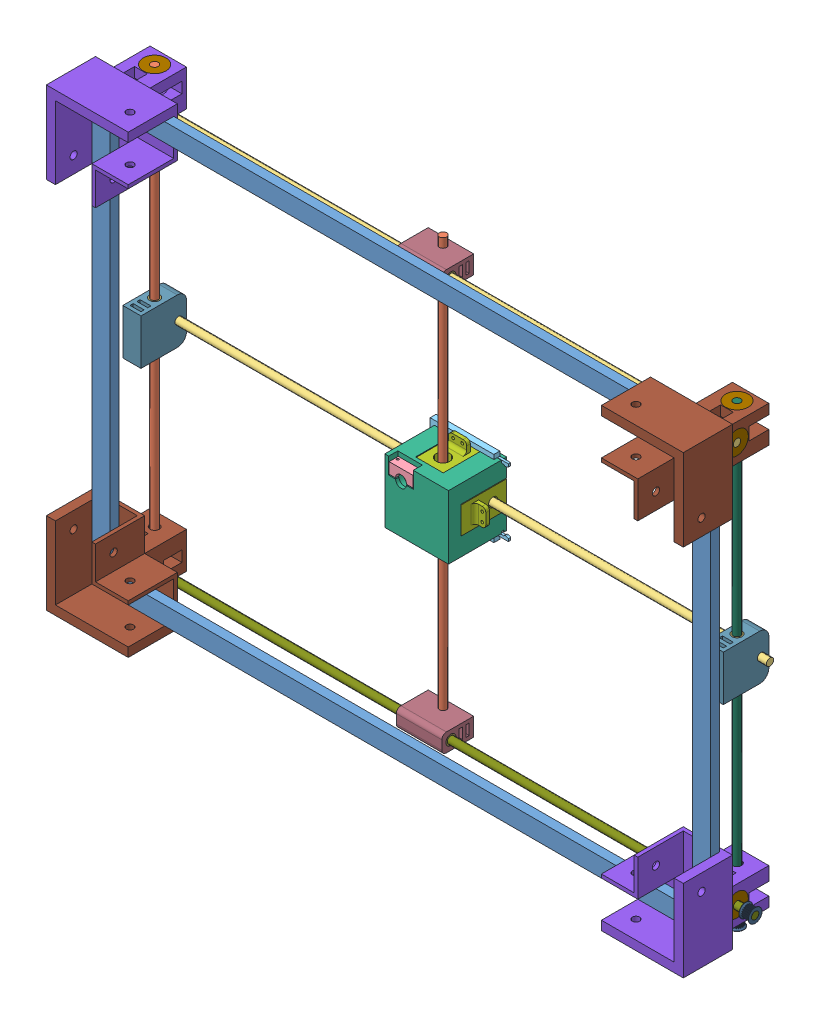
SolidWorks assembly Assemblage_XY, configuration Défaut. Lengths in mm.
Overall size (710 510 120.3).
50 component instances, 16 part files, 70 mates.
Components (placement in the parent):
- Cadre_XY-1: Cadre_XY [Défaut] at (379.0068 -247.2078 675) size (680 480 10)
- AXE_8X480-2: AXE_8X480 [Défaut] at (-280.9932 -247.2078 636) x (0.987721 0 0.156231) z (0 1 0) size (8 8 480)
- AXE_8X680-1: AXE_8X680 [Défaut] at (379.0068 212.7922 656) x (0 0.013067 0.999915) z (-1 0 0) size (8 8 680)
- AXE_8X480-3: AXE_8X480 [Défaut] at (39.6568 232.7922 639.7) x (0.999527 0 0.030742) z (0 -1 0) size (8 8 480)
- AXE_8X680-3: AXE_8X680 [Défaut] at (-300.9932 -14.107 619.7) x (0 -0.696158 -0.717888) z (1 0 0) size (8 8 680)
- P3DMIPC-Tête_complete-1: P3DMIPC-Tête_complete [Défaut] at (-4.5359 -0.7369 635.2981) x (0 1 0) z (1 0 0) size (94 64.01 96.63)
  - P3DMIPC-Clip_Buse_E3D-1: P3DMIPC-Clip_Buse_E3D [Défaut] at (17.0518 23.4109 40.0035) x (1 0 0) z (0 1 0) size (12 26 10)
  - P3DMIPC-Clip_tête-1: P3DMIPC-Clip_tête [Défaut] at (26.9018 -25.0891 4.5597) x (1 0 0) z (0 -1 0) size (84 92 6.55)
  - P3DMIPC-Porte_Buse_E3DX1-1: P3DMIPC-Porte_Buse_E3DX1 [Défaut] at (22.03 33.4019 79.1927) x (0 0 1) z (0 -1 0) size (70 70 64)
  - P3DMIPC-Chariot-1: P3DMIPC-Chariot [Défaut] at (-48.37 -30.5981 79.1927) size (94 50 94)
- Angle_magique_G-1: Angle_magique_G [Défaut] at (379.0068 -247.2078 675) x (-1 0 0) z (0 0 -1) size (90 90 104)
- F608ZZ-1: F608ZZ [Défaut] at (372.0068 -227.2078 656) x (0 -0.924225 -0.381849) z (1 0 0) size (25 25 7)
- Angle_magique_G-4: Angle_magique_G [Défaut] at (-300.9932 232.7922 675) x (1 0 0) z (0 0 -1) size (90 90 104)
- pulley_gt2_3mm_20t-10: pulley_gt2_3mm_20t [Défaut] at (-280.9932 209.5422 636) x (0.106795 0 0.994281) z (0 1 0) size (15 15 10.5)
- pulley_gt2_3mm_20t-11: pulley_gt2_3mm_20t [Défaut] at (-277.7432 212.7922 656) x (0 0.106795 0.994281) z (-1 0 0) size (15 15 10.5)
- pulley_gt2_3mm_20t-12: pulley_gt2_3mm_20t [Défaut] at (-280.9932 -236.4578 636) x (-0.771074 0 0.636745) z (0 1 0) size (15 15 10.5)
- pulley_gt2_3mm_20t-13: pulley_gt2_3mm_20t [Défaut] at (-277.7432 -227.2078 656) x (0 0.106795 0.994281) z (-1 0 0) size (15 15 10.5)
- pulley_gt2_3mm_20t-15: pulley_gt2_3mm_20t [Défaut] at (359.0068 222.0422 636) x (-0.106795 0 0.994281) z (0 -1 0) size (15 15 10.5)
- pulley_gt2_3mm_20t-16: pulley_gt2_3mm_20t [Défaut] at (368.2568 212.7922 656) x (0 0.106795 0.994281) z (-1 0 0) size (15 15 10.5)
- F608ZZ-2: F608ZZ [Défaut] at (-280.9932 225.7922 636) x (-0.546944 0 0.837169) z (0 1 0) size (25 25 7)
- F608ZZ-3: F608ZZ [Défaut] at (-293.9932 212.7922 656) x (0 0 1) z (-1 0 0) size (25 25 7)
- F608ZZ-4: F608ZZ [Défaut] at (-293.9932 -227.2078 656) x (0 0 1) z (-1 0 0) size (25 25 7)
- F608ZZ-5: F608ZZ [Défaut] at (-280.9932 -240.2078 636) x (-0.924225 0 -0.381849) z (0 -1 0) size (25 25 7)
- F608ZZ-6: F608ZZ [Défaut] at (359.0068 -240.2078 636) x (-0.546944 0 0.837169) z (0 -1 0) size (25 25 7)
- F608ZZ-7: F608ZZ [Défaut] at (372.0068 212.7922 656) x (0 0 1) z (1 0 0) size (25 25 7)
- F608ZZ-8: F608ZZ [Défaut] at (359.0068 225.7922 636) x (0 0 1) z (0 1 0) size (25 25 7)
- Angle_magique_D-1: Angle_magique_D [Défaut] at (-300.9932 -247.2078 675) x (0 1 0) z (0 0 -1) size (90 90 104)
- Angle_magique_D-2: Angle_magique_D [Défaut] at (379.0068 232.7922 675) x (0 -1 0) z (0 0 -1) size (90 90 104)
- Assemblage_glissière_block_belt_palier_AR-1: Assemblage_glissière_block_belt_palier_AR [Défaut] at (160.1817 -186.4667 609.4689) x (0 -1 0) z (-1 0 0) size (20 35 50)
  - ultimaker_cuivre_fritté_douille_8mmx11mmx22 mm-1: ultimaker_cuivre_fritté_douille_8mmx11mmx22 mm [Défaut] at (40.7411 46.5311 95.5249) size (11 11 22)
  - ultimaker_cuivre_fritté_douille_8mmx11mmx22 mm-2: ultimaker_cuivre_fritté_douille_8mmx11mmx22 mm [Défaut] at (40.7411 46.5311 123.5249) size (11 11 22)
  - Glisière_block_belt_AR-2: Glisière_block_belt_AR [Défaut] at (50.7411 14.5311 95.5249) size (20 35 50)
- Assemblage_glissière_block_belt_palier_AR-2: Assemblage_glissière_block_belt_palier_AR [Défaut] at (-80.8682 172.0511 609.4689) x (0 1 0) z (1 0 0) size (20 35 50)
  - ultimaker_cuivre_fritté_douille_8mmx11mmx22 mm-1: ultimaker_cuivre_fritté_douille_8mmx11mmx22 mm [Défaut] at (40.7411 46.5311 95.5249) size (11 11 22)
  - ultimaker_cuivre_fritté_douille_8mmx11mmx22 mm-2: ultimaker_cuivre_fritté_douille_8mmx11mmx22 mm [Défaut] at (40.7411 46.5311 123.5249) size (11 11 22)
  - Glisière_block_belt_AR-2: Glisière_block_belt_AR [Défaut] at (50.7411 14.5311 95.5249) size (20 35 50)
- pulley_gt2_3mm_20t-17: pulley_gt2_3mm_20t [Défaut] at (368.2568 -227.2078 656) x (0 0.106795 0.994281) z (-1 0 0) size (15 15 10.5)
- pulley_gt2_3mm_20t-18: pulley_gt2_3mm_20t [Défaut] at (359.0068 -223.9578 636) x (0.203502 0 0.979074) z (0 -1 0) size (15 15 10.5)
- Assemblage_glissière_block_belt_palier_GD-1: Assemblage_glissière_block_belt_palier_GD [Défaut] at (364.4936 -89.107 631.6132) x (-1 0 0) z (0 1 0) size (20 50 50)
  - Glisière_block_belt_GD-1: Glisière_block_belt_GD [Défaut] at (15.4869 -20.6132 50) size (20 50 50)
  - ultimaker_cuivre_fritté_douille_8mmx11mmx22 mm-1: ultimaker_cuivre_fritté_douille_8mmx11mmx22 mm [Défaut] at (5.4869 4.3868 50) size (11 11 22)
  - ultimaker_cuivre_fritté_douille_8mmx11mmx22 mm-2: ultimaker_cuivre_fritté_douille_8mmx11mmx22 mm [Défaut] at (5.4869 4.3868 78) size (11 11 22)
- Assemblage_glissière_block_belt_palier_GD-2: Assemblage_glissière_block_belt_palier_GD [Défaut] at (-286.4801 60.893 631.6132) x (1 0 0) z (0 -1 0) size (20 50 50)
  - Glisière_block_belt_GD-1: Glisière_block_belt_GD [Défaut] at (15.4869 -20.6132 50) size (20 50 50)
  - ultimaker_cuivre_fritté_douille_8mmx11mmx22 mm-1: ultimaker_cuivre_fritté_douille_8mmx11mmx22 mm [Défaut] at (5.4869 4.3868 50) size (11 11 22)
  - ultimaker_cuivre_fritté_douille_8mmx11mmx22 mm-2: ultimaker_cuivre_fritté_douille_8mmx11mmx22 mm [Défaut] at (5.4869 4.3868 78) size (11 11 22)
- AXE_8X500_Moteur-1: AXE_8X500_Moteur [Défaut] at (359.0068 -267.2078 636) x (0.283264 0 -0.959042) z (0 1 0) size (8 8 500)
- AXE_8X700_Moteur-1: AXE_8X700_Moteur [Défaut] at (399.0068 -227.2078 656) x (0 0 1) z (-1 0 0) size (8 8 700)
- pulley_gt2_3mm_20t-19: pulley_gt2_3mm_20t [Défaut] at (359.0068 -255.7078 636) x (0.203502 0 0.979074) z (0 -1 0) size (15 15 10.5)
- pulley_gt2_3mm_20t-20: pulley_gt2_3mm_20t [Défaut] at (387.5068 -227.2078 656) x (0 0.203502 0.979074) z (1 0 0) size (15 15 10.5)
Mates (geometry in assembly coordinates):
- Coaxiale1: concentric anti-aligned: cylinder of AXE_8X680-3 through (379.0068 -14.107 619.7) axis (-1 0 0) radius 4; cylinder of P3DMIPC-Tête_complete-1/P3DMIPC-Chariot-1 through (70.6568 -14.107 619.7) axis (1 0 0) radius 5
- Coaxiale2: concentric anti-aligned: cylinder of AXE_8X480-3 through (39.6568 -247.2078 639.7) axis (0 1 0) radius 4; cylinder of P3DMIPC-Tête_complete-1/P3DMIPC-Chariot-1 through (39.6568 -45.107 639.7) axis (0 -1 0) radius 5
- Coïncidente14: coincident anti-aligned: plane of Cadre_XY-1 through (379.0068 -247.2078 675) normal (0 0 -1); plane of Angle_magique_G-1 through (379.0068 -247.2078 675) normal (0 0 1)
- Coïncidente15: coincident anti-aligned: plane of Cadre_XY-1 through (379.0068 -247.2078 685) normal (1 0 0); plane of Angle_magique_G-1 through (379.0068 -247.2078 725) normal (-1 0 0)
- Coïncidente16: coincident anti-aligned: plane of Cadre_XY-1 through (379.0068 -247.2078 685) normal (0 -1 0); plane of Angle_magique_G-1 through (299.0068 -247.2078 725) normal (0 1 0)
- Coïncidente27: coincident anti-aligned: plane of Cadre_XY-1 through (379.0068 -247.2078 675) normal (0 0 -1); plane of Angle_magique_G-4 through (-300.9932 232.7922 675) normal (0 0 1)
- Coïncidente28: coincident anti-aligned: plane of Cadre_XY-1 through (379.0068 232.7922 685) normal (0 1 0); plane of Angle_magique_G-4 through (-220.9932 232.7922 725) normal (0 -1 0)
- Coïncidente29: coincident anti-aligned: plane of Cadre_XY-1 through (-300.9932 -247.2078 685) normal (-1 0 0); plane of Angle_magique_G-4 through (-300.9932 232.7922 725) normal (1 0 0)
- Coaxiale17: concentric anti-aligned: cylinder of AXE_8X680-1 through (-300.9932 212.7922 656) axis (1 0 0) radius 4; cylinder of pulley_gt2_3mm_20t-11 through (-277.7432 212.7922 656) axis (-1 0 0) radius 4
- Coaxiale18: concentric aligned: cylinder of AXE_8X680-1 through (-300.9932 212.7922 656) axis (1 0 0) radius 4; cylinder of Angle_magique_G-4 through (-310.9932 212.7922 656) axis (1 0 0) radius 5
- Coïncidente30: coincident aligned: plane of Cadre_XY-1 through (-300.9932 -247.2078 685) normal (-1 0 0); plane of AXE_8X680-1 through (-300.9932 212.7922 656) normal (-1 0 0)
- Distance2: distance = 2.75 mm anti-aligned: plane of pulley_gt2_3mm_20t-11 through (-278.7432 212.7922 656) normal (1 0 0); plane of Angle_magique_G-4 through (-275.9932 192.7922 621) normal (-1 0 0)
- Coaxiale19: concentric anti-aligned: cylinder of AXE_8X680-1 through (-300.9932 212.7922 656) axis (1 0 0) radius 4; cylinder of pulley_gt2_3mm_20t-16 through (368.2568 212.7922 656) axis (-1 0 0) radius 4
- Coaxiale24: concentric aligned: cylinder of AXE_8X480-2 through (-280.9932 232.7922 636) axis (0 -1 0) radius 4; cylinder of Angle_magique_G-4 through (-280.9932 232.7923 636) axis (0 -1 0) radius 5
- Coaxiale25: concentric anti-aligned: cylinder of AXE_8X480-2 through (-280.9932 232.7922 636) axis (0 -1 0) radius 4; cylinder of pulley_gt2_3mm_20t-10 through (-280.9932 209.5422 636) axis (0 1 0) radius 4
- Coïncidente34: coincident aligned: plane of Cadre_XY-1 through (379.0068 232.7922 685) normal (0 1 0); plane of AXE_8X480-2 through (-280.9932 232.7922 636) normal (0 1 0)
- Distance4: distance = 2.75 mm anti-aligned: plane of pulley_gt2_3mm_20t-10 through (-280.9932 210.5422 636) normal (0 -1 0); plane of Angle_magique_G-4 through (-275.9932 207.7922 621) normal (0 1 0)
- Coaxiale26: concentric anti-aligned: cylinder of AXE_8X480-2 through (-280.9932 232.7922 636) axis (0 -1 0) radius 4; cylinder of pulley_gt2_3mm_20t-12 through (-280.9932 -236.4578 636) axis (0 1 0) radius 4
- Coïncidente44: coincident anti-aligned: plane of Cadre_XY-1 through (379.0068 -247.2078 675) normal (0 0 -1); plane of Angle_magique_D-1 through (-300.9932 -247.2078 675) normal (0 0 1)
- Coïncidente45: coincident anti-aligned: plane of Cadre_XY-1 through (379.0068 -247.2078 685) normal (0 -1 0); plane of Angle_magique_D-1 through (-300.9932 -247.2078 725) normal (0 1 0)
- Coïncidente46: coincident anti-aligned: plane of Cadre_XY-1 through (-300.9932 -247.2078 685) normal (-1 0 0); plane of Angle_magique_D-1 through (-300.9932 -167.2078 725) normal (1 0 0)
- Distance10: distance = 2.75 mm anti-aligned: plane of Angle_magique_D-1 through (-260.9932 -222.2078 621) normal (0 -1 0); plane of pulley_gt2_3mm_20t-12 through (-280.9932 -224.9578 636) normal (0 1 0)
- Coïncidente51: coincident anti-aligned: plane of Cadre_XY-1 through (379.0068 -247.2078 675) normal (0 0 -1); plane of Angle_magique_D-2 through (379.0068 232.7922 675) normal (0 0 1)
- Coïncidente52: coincident anti-aligned: plane of Cadre_XY-1 through (379.0068 232.7922 685) normal (0 1 0); plane of Angle_magique_D-2 through (379.0068 232.7922 725) normal (0 -1 0)
- Coïncidente53: coincident anti-aligned: plane of Cadre_XY-1 through (379.0068 -247.2078 685) normal (1 0 0); plane of Angle_magique_D-2 through (379.0068 152.7922 725) normal (-1 0 0)
- Distance11: distance = 2.75 mm anti-aligned: plane of pulley_gt2_3mm_20t-15 through (359.0068 210.5422 636) normal (0 -1 0); plane of Angle_magique_D-2 through (339.0068 207.7922 621) normal (0 1 0)
- Distance12: distance = 2.75 mm anti-aligned: plane of Angle_magique_D-2 through (354.0068 207.7922 621) normal (1 0 0); plane of pulley_gt2_3mm_20t-16 through (356.7568 212.7922 656) normal (-1 0 0)
- Coaxiale39: concentric anti-aligned: cylinder of AXE_8X680-1 through (-300.9932 212.7922 656) axis (1 0 0) radius 4; cylinder of Assemblage_glissière_block_belt_palier_AR-2/ultimaker_cuivre_fritté_douille_8mmx11mmx22 mm-1 through (36.6568 212.7922 656) axis (-1 0 0) radius 4
- Coaxiale42: concentric anti-aligned: cylinder of AXE_8X480-3 through (39.6568 -247.2078 639.7) axis (0 1 0) radius 4; cylinder of Assemblage_glissière_block_belt_palier_AR-2/Glisière_block_belt_AR-2 through (39.6568 222.7922 639.7) axis (0 -1 0) radius 4
- Coaxiale43: concentric aligned: cylinder of AXE_8X480-3 through (39.6568 -247.2078 639.7) axis (0 1 0) radius 4; cylinder of Assemblage_glissière_block_belt_palier_AR-1/Glisière_block_belt_AR-2 through (39.6568 -237.2078 639.7) axis (0 1 0) radius 4
- Coaxiale50: concentric anti-aligned: cylinder of F608ZZ-7 through (377.5068 212.7922 656) axis (-1 0 0) radius 11; cylinder of Angle_magique_D-2 through (372.0068 212.7922 656) axis (1 0 0) radius 11
- Coïncidente63: coincident anti-aligned: plane of F608ZZ-7 through (372.0068 212.7922 656) normal (-1 0 0); plane of Angle_magique_D-2 through (372.0068 212.7922 656) normal (1 0 0)
- Coaxiale51: concentric anti-aligned: cylinder of F608ZZ-8 through (359.0068 231.2922 636) axis (0 -1 0) radius 11; cylinder of Angle_magique_D-2 through (359.0068 225.7922 636) axis (0 1 0) radius 11
- Coïncidente64: coincident anti-aligned: plane of F608ZZ-8 through (359.0068 225.7922 636) normal (0 -1 0); plane of Angle_magique_D-2 through (359.0068 225.7922 636) normal (0 1 0)
- Coïncidente65: coincident anti-aligned: plane of Angle_magique_G-4 through (-280.9932 225.7922 636) normal (0 1 0); plane of F608ZZ-2 through (-280.9932 225.7922 636) normal (0 -1 0)
- Coaxiale53: concentric anti-aligned: cylinder of Angle_magique_G-4 through (-280.9932 225.7922 636) axis (0 1 0) radius 11; cylinder of F608ZZ-2 through (-280.9932 231.2922 636) axis (0 -1 0) radius 11
- Coaxiale54: concentric anti-aligned: cylinder of Angle_magique_G-4 through (-293.9932 212.7922 656) axis (-1 0 0) radius 11; cylinder of F608ZZ-3 through (-299.4932 212.7922 656) axis (1 0 0) radius 11
- Coïncidente66: coincident anti-aligned: plane of Angle_magique_G-4 through (-293.9932 212.7922 656) normal (-1 0 0); plane of F608ZZ-3 through (-293.9932 212.7922 656) normal (1 0 0)
- Coaxiale57: concentric anti-aligned: cylinder of F608ZZ-4 through (-299.4932 -227.2078 656) axis (1 0 0) radius 11; cylinder of Angle_magique_D-1 through (-293.9932 -227.2078 656) axis (-1 0 0) radius 11
- Coïncidente69: coincident anti-aligned: plane of F608ZZ-4 through (-293.9932 -227.2078 656) normal (1 0 0); plane of Angle_magique_D-1 through (-293.9932 -227.2078 656) normal (-1 0 0)
- Coïncidente70: coincident anti-aligned: plane of F608ZZ-5 through (-280.9932 -240.2078 636) normal (0 1 0); plane of Angle_magique_D-1 through (-280.9932 -240.2078 636) normal (0 -1 0)
- Coaxiale58: concentric anti-aligned: cylinder of F608ZZ-5 through (-280.9932 -245.7078 636) axis (0 1 0) radius 11; cylinder of Angle_magique_D-1 through (-280.9932 -240.2078 636) axis (0 -1 0) radius 11
- Distance14: distance = 2.75 mm anti-aligned: plane of Angle_magique_G-1 through (354.0068 -222.2078 621) normal (0 -1 0); plane of pulley_gt2_3mm_20t-18 through (359.0068 -224.9578 636) normal (0 1 0)
- Distance15: distance = 2.75 mm anti-aligned: plane of Angle_magique_G-1 through (354.0068 -207.2078 621) normal (1 0 0); plane of pulley_gt2_3mm_20t-17 through (356.7568 -227.2078 656) normal (-1 0 0)
- Coïncidente73: coincident anti-aligned: plane of Angle_magique_G-1 through (359.0068 -240.2078 636) normal (0 -1 0); plane of F608ZZ-6 through (359.0068 -240.2078 636) normal (0 1 0)
- Coaxiale61: concentric anti-aligned: cylinder of Angle_magique_G-1 through (359.0068 -240.2078 636) axis (0 -1 0) radius 11; cylinder of F608ZZ-6 through (359.0068 -245.7078 636) axis (0 1 0) radius 11
- Coïncidente74: coincident anti-aligned: plane of Angle_magique_G-1 through (372.0068 -227.2078 656) normal (1 0 0); plane of F608ZZ-1 through (372.0068 -227.2078 656) normal (-1 0 0)
- Coaxiale62: concentric anti-aligned: cylinder of Angle_magique_G-1 through (372.0068 -227.2078 656) axis (1 0 0) radius 11; cylinder of F608ZZ-1 through (377.5068 -227.2078 656) axis (-1 0 0) radius 11
- Coaxiale64: concentric anti-aligned: cylinder of AXE_8X680-3 through (379.0068 -14.107 619.7) axis (-1 0 0) radius 4; cylinder of Assemblage_glissière_block_belt_palier_GD-1/Glisière_block_belt_GD-1 through (349.0068 -14.107 619.7) axis (1 0 0) radius 4
- Coaxiale65: concentric anti-aligned: cylinder of Assemblage_glissière_block_belt_palier_GD-2/ultimaker_cuivre_fritté_douille_8mmx11mmx22 mm-1 through (-280.9932 -11.107 636) axis (0 1 0) radius 4; cylinder of AXE_8X480-2 through (-280.9932 232.7922 636) axis (0 -1 0) radius 4
- Coaxiale66: concentric aligned: cylinder of AXE_8X680-3 through (379.0068 -14.107 619.7) axis (-1 0 0) radius 4; cylinder of Assemblage_glissière_block_belt_palier_GD-2/Glisière_block_belt_GD-1 through (-270.9932 -14.107 619.7) axis (-1 0 0) radius 4
- Coïncidente75: coincident aligned: plane of Cadre_XY-1 through (-300.9932 -247.2078 685) normal (-1 0 0); plane of AXE_8X680-3 through (-300.9932 -14.107 619.7) normal (-1 0 0)
- Coïncidente76: coincident aligned: plane of Cadre_XY-1 through (379.0068 -247.2078 685) normal (0 -1 0); plane of AXE_8X480-3 through (39.6568 -247.2078 639.7) normal (0 -1 0)
- Distance17: distance = 2.75 mm anti-aligned: plane of pulley_gt2_3mm_20t-13 through (-278.7432 -227.2078 656) normal (1 0 0); plane of Angle_magique_D-1 through (-275.9932 -222.2078 621) normal (-1 0 0)
- Coaxiale67: concentric anti-aligned: cylinder of Angle_magique_G-1 through (389.0068 -227.2078 656) axis (-1 0 0) radius 5; cylinder of AXE_8X700_Moteur-1 through (-300.9932 -227.2078 656) axis (1 0 0) radius 4
- Coaxiale68: concentric aligned: cylinder of Assemblage_glissière_block_belt_palier_AR-1/ultimaker_cuivre_fritté_douille_8mmx11mmx22 mm-2 through (14.6568 -227.2078 656) axis (1 0 0) radius 4; cylinder of AXE_8X700_Moteur-1 through (-300.9932 -227.2078 656) axis (1 0 0) radius 4
- Coaxiale69: concentric aligned: cylinder of Angle_magique_D-1 through (-310.9932 -227.2078 656) axis (1 0 0) radius 5; cylinder of AXE_8X700_Moteur-1 through (-300.9932 -227.2078 656) axis (1 0 0) radius 4
- Coïncidente80: coincident aligned: plane of Cadre_XY-1 through (-300.9932 -247.2078 685) normal (-1 0 0); plane of AXE_8X700_Moteur-1 through (-300.9932 -227.2078 656) normal (-1 0 0)
- Coaxiale70: concentric anti-aligned: cylinder of pulley_gt2_3mm_20t-13 through (-277.7432 -227.2078 656) axis (-1 0 0) radius 4; cylinder of AXE_8X700_Moteur-1 through (-300.9932 -227.2078 656) axis (1 0 0) radius 4
- Coaxiale71: concentric anti-aligned: cylinder of pulley_gt2_3mm_20t-17 through (368.2568 -227.2078 656) axis (-1 0 0) radius 4; cylinder of AXE_8X700_Moteur-1 through (-300.9932 -227.2078 656) axis (1 0 0) radius 4
- Coaxiale72: concentric aligned: cylinder of Assemblage_glissière_block_belt_palier_GD-1/ultimaker_cuivre_fritté_douille_8mmx11mmx22 mm-2 through (359.0068 10.893 636) axis (0 -1 0) radius 4; cylinder of AXE_8X500_Moteur-1 through (359.0068 232.7922 636) axis (0 -1 0) radius 4
- Coaxiale73: concentric anti-aligned: cylinder of Angle_magique_G-1 through (359.0068 -247.2078 636) axis (0 1 0) radius 5; cylinder of AXE_8X500_Moteur-1 through (359.0068 232.7922 636) axis (0 -1 0) radius 4
- Coaxiale74: concentric aligned: cylinder of Angle_magique_D-2 through (359.0068 242.7922 636) axis (0 -1 0) radius 5; cylinder of AXE_8X500_Moteur-1 through (359.0068 232.7922 636) axis (0 -1 0) radius 4
- Coaxiale75: concentric aligned: cylinder of pulley_gt2_3mm_20t-15 through (359.0068 222.0422 636) axis (0 -1 0) radius 4; cylinder of AXE_8X500_Moteur-1 through (359.0068 232.7922 636) axis (0 -1 0) radius 4
- Coaxiale76: concentric aligned: cylinder of pulley_gt2_3mm_20t-18 through (359.0068 -223.9578 636) axis (0 -1 0) radius 4; cylinder of AXE_8X500_Moteur-1 through (359.0068 232.7922 636) axis (0 -1 0) radius 4
- Coïncidente81: coincident aligned: plane of Cadre_XY-1 through (379.0068 232.7922 685) normal (0 1 0); plane of AXE_8X500_Moteur-1 through (359.0068 232.7922 636) normal (0 1 0)
- Coaxiale77: concentric aligned: cylinder of AXE_8X500_Moteur-1 through (359.0068 232.7922 636) axis (0 -1 0) radius 4; cylinder of pulley_gt2_3mm_20t-19 through (359.0068 -255.7078 636) axis (0 -1 0) radius 4
- Coïncidente82: coincident aligned: plane of AXE_8X500_Moteur-1 through (359.0068 -267.2078 636) normal (0 -1 0); plane of pulley_gt2_3mm_20t-19 through (359.0068 -267.2078 636) normal (0 -1 0)
- Coïncidente83: coincident aligned: plane of AXE_8X700_Moteur-1 through (399.0068 -227.2078 656) normal (1 0 0); plane of pulley_gt2_3mm_20t-20 through (399.0068 -227.2078 656) normal (1 0 0)
- Coaxiale78: concentric aligned: cylinder of AXE_8X700_Moteur-1 through (-300.9932 -227.2078 656) axis (1 0 0) radius 4; cylinder of pulley_gt2_3mm_20t-20 through (387.5068 -227.2078 656) axis (1 0 0) radius 4
